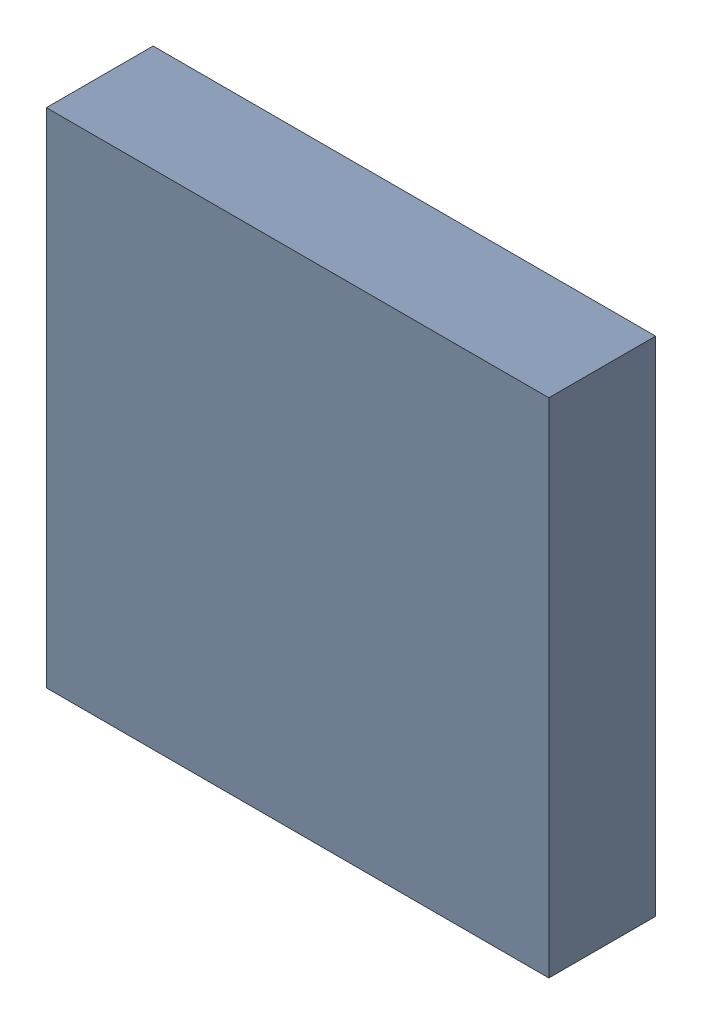
SolidWorks assembly IC3, configuration Standard. Lengths in mm.
Overall size (4 4 0.85).
2 component instances, 1 part files, 0 mates.
Components (placement in the parent):
- 885544688-1: 885544688 [Standard] at (8.35 -16.75 0) size (4 4 0.85)
  - Extruded_9-1: Extruded_9 [Standard] at origin size (4 4 0.85)
